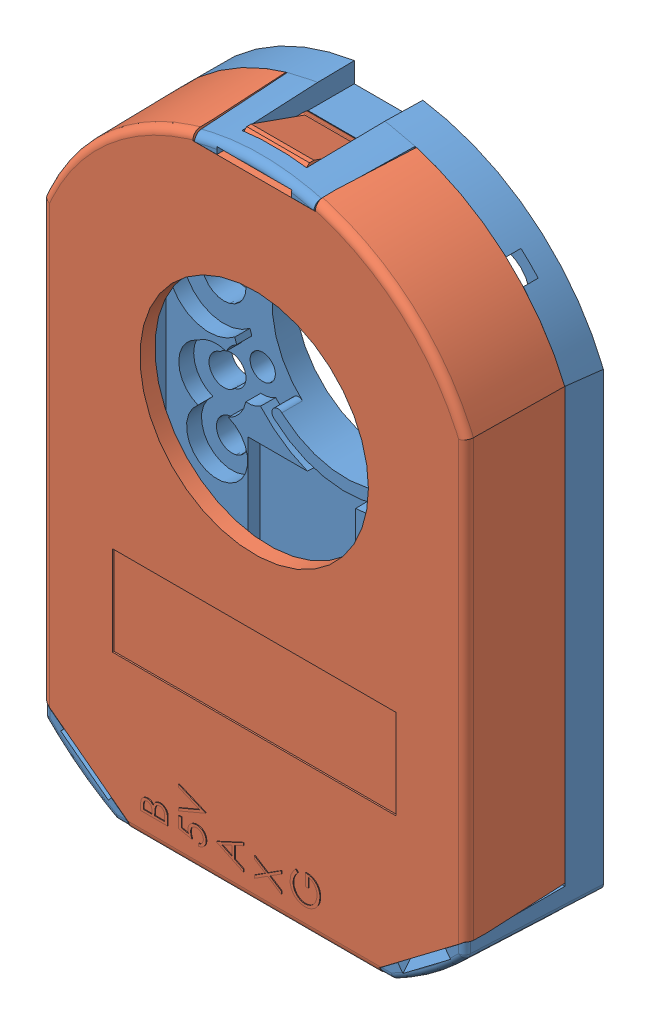
SolidWorks assembly AMT102, configuration ﾃﾞﾌｫﾙﾄ. Lengths in mm.
Overall size (28.78 43.39 9.1).
2 component instances, 2 part files, 3 mates.
Components (placement in the parent):
- AMT-102-Base-REV-K-1: AMT-102-Base-REV-K [ﾃﾞﾌｫﾙﾄ] at (-12.1137 4.4823 -5.23) x (-1 0 0) z (0 0 -1) size (28.78 43.39 9.08)
- AMT-102-Top-Cover-REV-I-1: AMT-102-Top-Cover-REV-I [ﾃﾞﾌｫﾙﾄ] at (-12.1137 4.4823 0) x (-1 0 0) z (0 0 -1) size (28.6 43.26 6.55)
Mates (geometry in assembly coordinates):
- 一致6: coincident anti-aligned: plane of AMT-102-Base-REV-K-1 through (-12.2253 -5.9377 4.9177) normal (0.017452 0 0.999848); plane of AMT-102-Top-Cover-REV-I-1 through (-12.2253 4.4823 4.9177) normal (-0.017452 0 -0.999848)
- 同心円2: concentric aligned: cone of AMT-102-Base-REV-K-1 through (-12.2253 4.4823 4.9177) axis (0.017452 0 0.999848); cone of AMT-102-Top-Cover-REV-I-1 through (-12.2253 4.4823 4.9177) axis (0.017452 0 0.999848)
- 一致7: coincident anti-aligned: unknown of AMT-102-Top-Cover-REV-I-1
